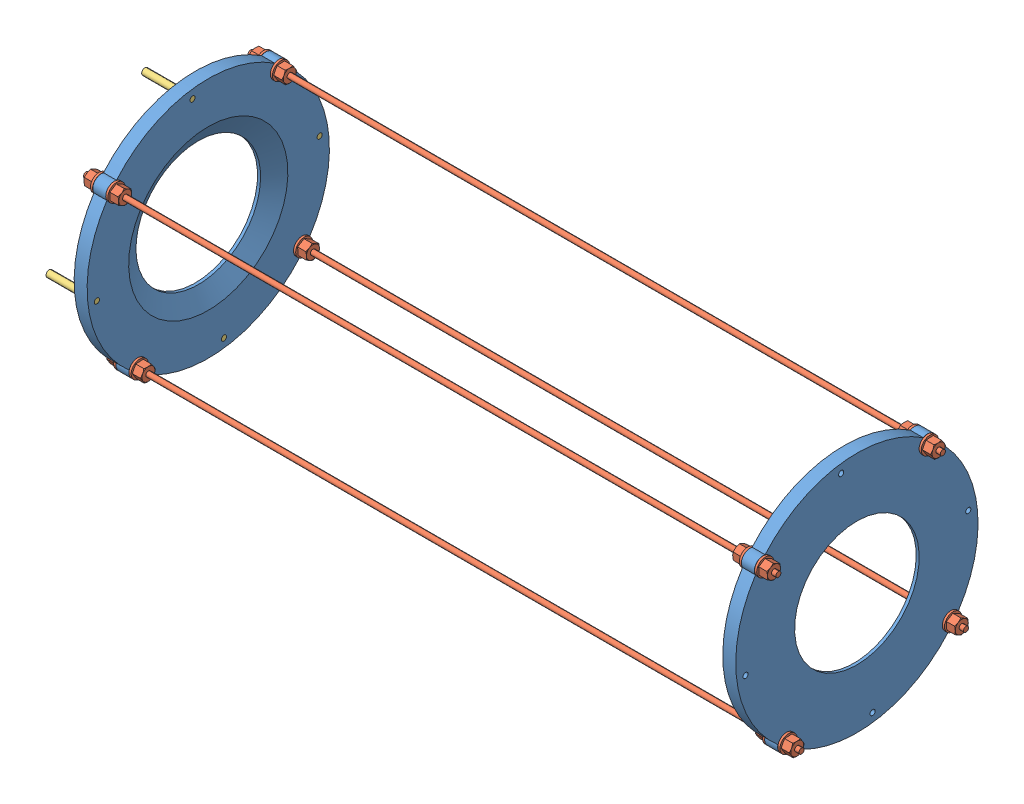
SolidWorks assembly Assem1, configuration Default. Lengths in mm.
Overall size (522.16 200.91 200.91).
10 component instances, 3 part files, 7 mates.
Components (placement in the parent):
- NO2 Tank Support Ring-1: NO2 Tank Support Ring [Default] at (-99.0557 283.0319 424.2921) x (0 -0.139785 0.990182) z (0 0.990182 0.139785) size (177.8 9.53 177.8)
- Joined Nut and Bolt 0.190 Rod-2: Joined Nut and Bolt 0.190 Rod [94758A105] at (-107.1202 351.9327 372.4383) x (0 -0.999131 -0.041685) z (-1 0 0) size (12.7 12.7 508)
- Joined Nut and Bolt 0.190 Rod-6: Joined Nut and Bolt 0.190 Rod [94758A105] at (-107.1202 334.8857 493.1929) x (0 0.041685 -0.999131) z (-1 0 0) size (12.7 12.7 508)
- Joined Nut and Bolt 0.190 Rod-7: Joined Nut and Bolt 0.190 Rod [94758A105] at (-107.1202 214.1311 476.1459) x (0 0.999131 0.041685) z (-1 0 0) size (12.7 12.7 508)
- Joined Nut and Bolt 0.190 Rod-8: Joined Nut and Bolt 0.190 Rod [94758A105] at (-107.1202 231.1781 355.3913) x (0 -0.041685 0.999131) z (-1 0 0) size (12.7 12.7 508)
- NO2 Tank Support Ring-3: NO2 Tank Support Ring [Default] at (386.4653 283.0319 424.2921) x (0 0.139785 -0.990182) z (0 0.990182 0.139785) size (177.8 9.53 177.8)
- Basic Aluminum Rod-1: Basic Aluminum Rod [Default] at (-124.4557 364.7714 435.8313) x (0 -0.280995 -0.959709) z (0 -0.959709 0.280995) size (4.83 34.92 4.83)
- Basic Aluminum Rod-2: Basic Aluminum Rod [Default] at (-124.4557 271.4927 506.0316) x (0 0.959709 -0.280995) z (0 -0.280995 -0.959709) size (4.83 34.92 4.83)
- Basic Aluminum Rod-3: Basic Aluminum Rod [Default] at (-124.4557 201.2924 412.7529) x (0 0.280995 0.959709) z (0 0.959709 -0.280995) size (4.83 34.92 4.83)
- Basic Aluminum Rod-4: Basic Aluminum Rod [Default] at (-124.4557 294.5711 342.5526) x (0 -0.959709 0.280995) z (0 0.280995 0.959709) size (4.83 34.92 4.83)
Mates (geometry in assembly coordinates):
- Coincident5: coincident: plane of NO2 Tank Support Ring-1 through (-89.5307 257.105 389.8417) normal (1 0 0); plane of Joined Nut and Bolt 0.190 Rod-2 through (-89.5307 351.7034 377.9328) normal (-1 0 0)
- Concentric15: concentric: cylinder of NO2 Tank Support Ring-1 through (-89.5307 351.9327 372.4383) axis (-1 0 0) radius 1.905; cylinder of Joined Nut and Bolt 0.190 Rod-2 through (-94.3567 351.9327 372.4383) axis (-1 0 0) radius 1.905
- Concentric16: concentric: cylinder of Joined Nut and Bolt 0.190 Rod-8 through (381.7663 231.1781 355.3913) axis (1 0 0) radius 1.905; cylinder of NO2 Tank Support Ring-3 through (376.9403 231.1781 355.3913) axis (1 0 0) radius 1.905
- Concentric17: concentric: cylinder of Joined Nut and Bolt 0.190 Rod-7 through (381.7663 214.1311 476.1459) axis (1 0 0) radius 1.905; cylinder of NO2 Tank Support Ring-3 through (376.9403 214.1311 476.1459) axis (1 0 0) radius 1.905
- Coincident7: coincident: plane of Joined Nut and Bolt 0.190 Rod-2 through (376.9403 351.7034 377.9328) normal (1 0 0); plane of NO2 Tank Support Ring-3 through (376.9403 248.5815 450.219) normal (-1 0 0)
- Concentric18: concentric: cylinder of NO2 Tank Support Ring-1 through (-102.2307 364.7714 435.8313) axis (1 0 0) radius 1.905; cylinder of Basic Aluminum Rod-1 through (-89.5307 364.7714 435.8313) axis (-1 0 0) radius 1.905
- Coincident8: coincident: plane of NO2 Tank Support Ring-1 through (-99.0557 257.105 389.8417) normal (-1 0 0); plane of Basic Aluminum Rod-1 through (-99.0557 364.7714 435.8313) normal (1 0 0)
